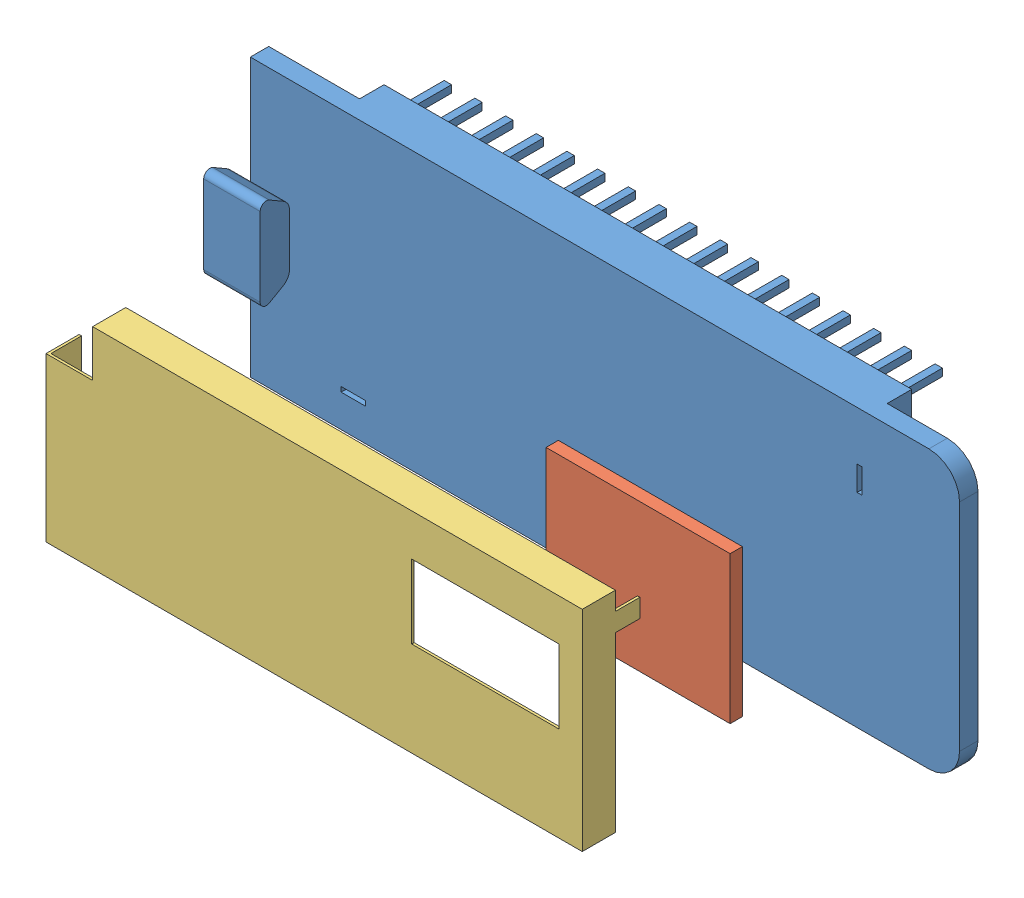
SolidWorks assembly c-zp, configuration 默认. Lengths in mm.
Overall size (59.2 22.6 29.9).
3 component instances, 3 part files, 0 mates.
Components (placement in the parent):
- C-DZB-1: C-DZB [默认] at origin size (59.2 22.6 9.6)
- C-YJP-1: C-YJP [默认] at (0 0 8) size (15 12 1)
- C-HZ-1: C-HZ [默认] at (-1 0 21.5) size (43.7 17.1 4.7)
